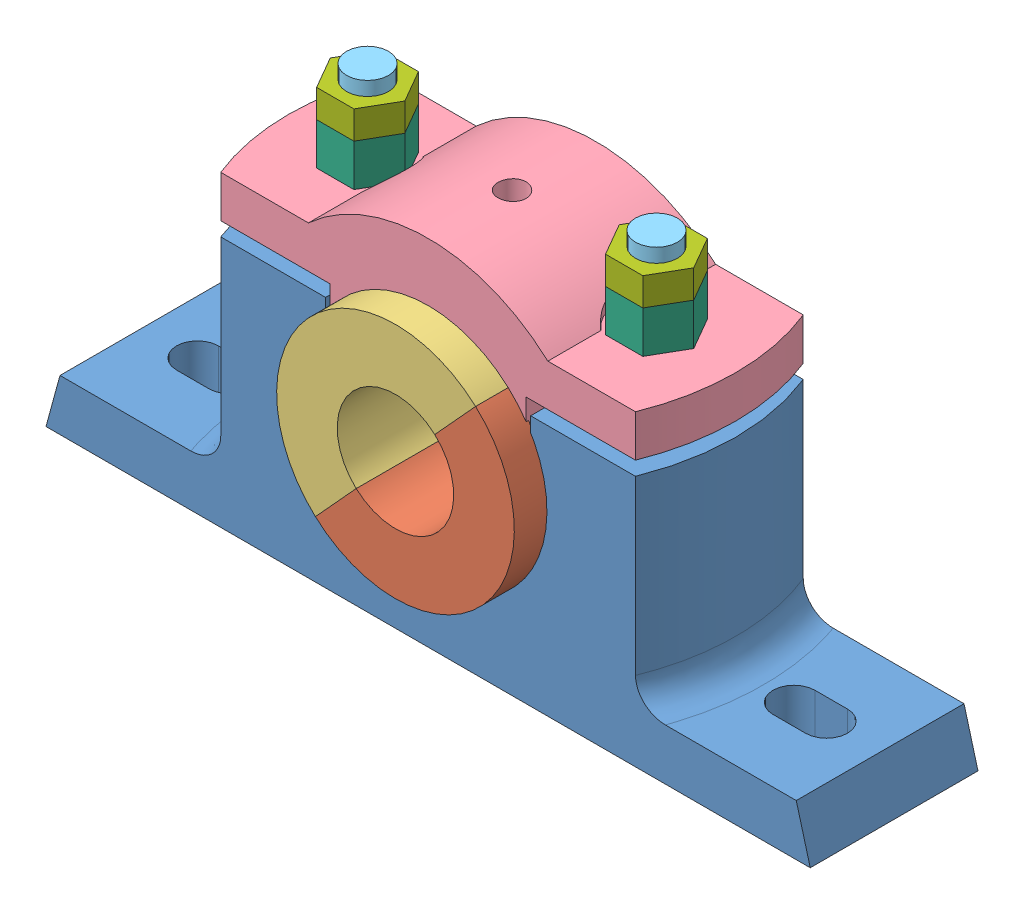
SolidWorks assembly Assem1, configuration Default. Lengths in mm.
Overall size (164 84 51).
10 component instances, 7 part files, 24 mates.
Components (placement in the parent):
- Casing-1: Casing [Default] at (67.4805 110.6561 116.9749) size (164 54 36)
- pp-1: pp [Default] at (67.4805 104.8326 116.4797) x (0 0 -1) z (0.674082 0.738657 0) size (51 25.5 51)
- pp1-2: pp1 [Default] at (67.4805 104.8326 116.4797) x (0 0 1) z (-0.674082 -0.738657 0) size (51 25.5 51)
- Cap-1: Cap [Default] at (67.4805 104.8326 116.9749) x (1 0 0) z (0 -1 0) size (96 36 32)
- bolt-1: bolt [Default] at (98.4805 74.8326 116.9749) x (0 0 1) z (1 0 0) size (19 82 19)
- nut 9-1: nut 9 [Default] at (98.4805 137.3326 116.9749) x (0.022178 0 -0.999754) z (0 1 0) size (14.03 16 9)
- nut 6-1: nut 6 [Default] at (98.4805 144.8326 116.9749) x (-0.854723 0 -0.519084) z (0 1 0) size (14.03 16 6)
- bolt-2: bolt [Default] at (36.4805 74.8326 116.9749) x (-1 0 0) z (0 0 1) size (19 82 19)
- nut 9-2: nut 9 [Default] at (36.4805 137.3326 116.9749) x (0.022178 0 0.999754) z (0 -1 0) size (14.03 16 9)
- nut 6-2: nut 6 [Default] at (36.4805 144.8326 116.9749) x (0.854723 0 0.519084) z (0 1 0) size (14.03 16 6)
Mates (geometry in assembly coordinates):
- Concentric4: concentric anti-aligned: cylinder of Casing-1 through (67.4805 104.8326 134.9749) axis (0 0 -1) radius 19; cylinder of pp-1 through (67.4805 104.8326 116.4797) axis (0 0 1) radius 19
- Concentric6: concentric anti-aligned: cylinder of pp-1 through (67.4805 104.8326 116.4797) axis (0 0 1) radius 12.5; cylinder of pp1-2 through (67.4805 104.8326 116.4797) axis (0 0 -1) radius 12.5
- Coincident5: coincident anti-aligned: plane of pp-1 through (67.4805 104.8326 116.4797) normal (-0.738657 0.674082 0); plane of pp1-2 through (67.4805 104.8326 116.4797) normal (0.738657 -0.674082 0)
- Coincident6: coincident aligned: plane of pp-1 through (59.0545 95.5994 90.9797) normal (0 0 -1); plane of pp1-2 through (59.0545 95.5994 90.9797) normal (0 0 -1)
- Parallel6: parallel aligned: plane of pp1-2 through (59.0545 95.5994 141.9797) normal (0 0 1); plane of Cap-1 through (67.4805 104.8326 134.9749) normal (0 0 1)
- Concentric25: concentric aligned: cylinder of Casing-1 through (36.4805 120.8326 116.9749) axis (0 1 0) radius 4.5; cylinder of Cap-1 through (36.4805 96.8326 116.9749) axis (0 1 0) radius 4.5
- Concentric26: concentric aligned: cylinder of pp1-2 through (67.4805 104.8326 116.4797) axis (0 0 -1) radius 17.5; cylinder of Cap-1 through (67.4805 104.8326 134.9749) axis (0 0 -1) radius 19
- Coincident33: coincident anti-aligned: plane of Casing-1 through (67.4805 74.8326 116.9749) normal (0 -1 0); plane of bolt-1 through (98.4805 74.8326 116.9749) normal (0 1 0)
- Concentric29: concentric anti-aligned: cylinder of Casing-1 through (98.4805 120.8326 116.9749) axis (0 1 0) radius 4.5; cylinder of bolt-1 through (98.4805 150.8326 116.9749) axis (0 -1 0) radius 4.5
- Concentric30: concentric anti-aligned: cylinder of bolt-1 through (98.4805 150.8326 116.9749) axis (0 -1 0) radius 4.5; cylinder of nut 9-1 through (98.4805 132.8326 116.9749) axis (0 1 0) radius 4
- Coincident34: coincident anti-aligned: plane of Cap-1 through (93.171 132.8326 134.9749) normal (0 1 0); plane of nut 9-1 through (98.4805 132.8326 116.9749) normal (0 -1 0)
- Concentric31: concentric anti-aligned: cylinder of bolt-1 through (98.4805 150.8326 116.9749) axis (0 -1 0) radius 4.5; cylinder of nut 6-1 through (98.4805 138.8326 116.9749) axis (0 1 0) radius 4
- Coincident35: coincident anti-aligned: plane of nut 9-1 through (98.4805 141.8326 116.9749) normal (0 1 0); plane of nut 6-1 through (98.4805 141.8326 116.9749) normal (0 -1 0)
- Parallel7: parallel aligned: plane of Cap-1 through (67.4805 104.8326 134.9749) normal (0 0 1); plane of nut 9-1 through (94.4805 141.8326 123.9031) normal (0 0 1)
- Parallel8: parallel aligned: plane of nut 9-1 through (94.4805 141.8326 123.9031) normal (0 0 1); plane of nut 6-1 through (94.4805 147.8326 123.9031) normal (0 0 1)
- Concentric32: concentric anti-aligned: cylinder of Casing-1 through (36.4805 120.8326 116.9749) axis (0 1 0) radius 4.5; cylinder of bolt-2 through (36.4805 150.8326 116.9749) axis (0 -1 0) radius 4.5
- Parallel9: parallel anti-aligned: plane of Casing-1 through (26.4805 74.8326 106.9749) normal (0 0 1); plane of bolt-2 through (26.9805 68.8326 107.4749) normal (0 0 -1)
- Coincident45: coincident anti-aligned: plane of Casing-1 through (67.4805 74.8326 116.9749) normal (0 -1 0); plane of bolt-2 through (36.4805 74.8326 116.9749) normal (0 1 0)
- Coincident46: coincident anti-aligned: plane of Cap-1 through (41.79 132.8326 134.9749) normal (0 1 0); plane of nut 9-2 through (36.4805 132.8326 116.9749) normal (0 -1 0)
- Concentric33: concentric aligned: cylinder of bolt-2 through (36.4805 150.8326 116.9749) axis (0 -1 0) radius 4.5; cylinder of nut 9-2 through (36.4805 141.8326 116.9749) axis (0 -1 0) radius 4
- Concentric34: concentric anti-aligned: cylinder of bolt-2 through (36.4805 150.8326 116.9749) axis (0 -1 0) radius 4.5; cylinder of nut 6-2 through (36.4805 138.8326 116.9749) axis (0 1 0) radius 4
- Coincident47: coincident anti-aligned: plane of nut 9-2 through (36.4805 141.8326 116.9749) normal (0 1 0); plane of nut 6-2 through (36.4805 141.8326 116.9749) normal (0 -1 0)
- Parallel10: parallel aligned: plane of nut 9-2 through (40.4805 132.8326 123.9031) normal (0 0 1); plane of nut 6-2 through (32.4805 147.8326 123.9031) normal (0 0 1)
- Parallel11: parallel aligned: plane of Cap-1 through (67.4805 104.8326 134.9749) normal (0 0 1); plane of nut 9-2 through (40.4805 132.8326 123.9031) normal (0 0 1)
